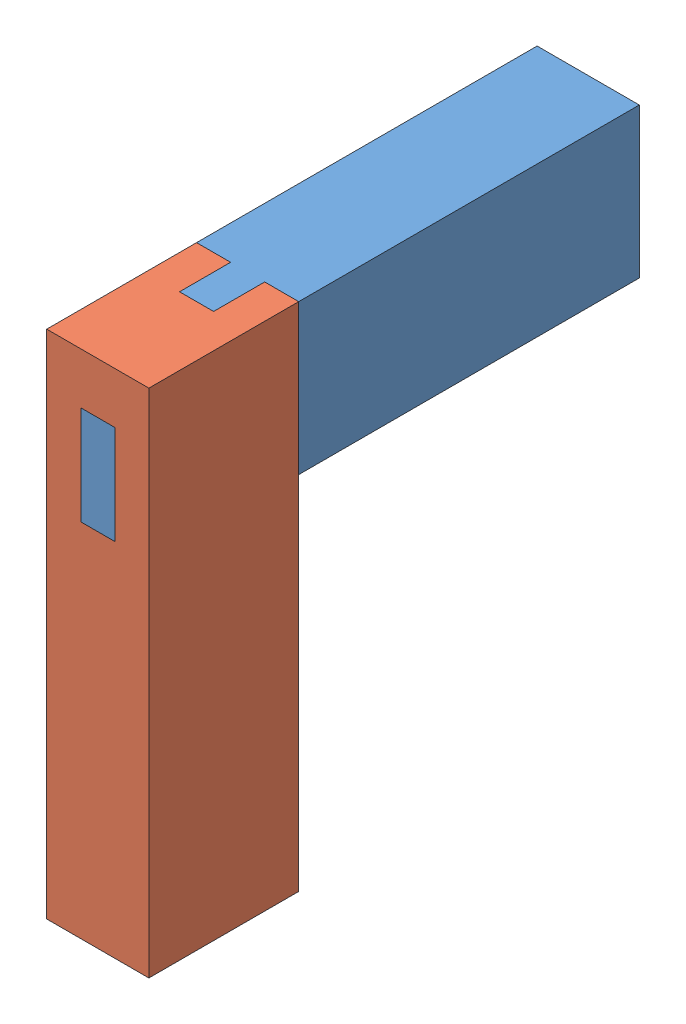
SolidWorks assembly M AND TENON EXPLODE, configuration Default. Lengths in mm.
Overall size (30 150 214.76).
2 component instances, 2 part files, 3 mates.
Components (placement in the parent):
- TENON-1: TENON [Default] at (-2.0324 11.2822 -9.248) size (30 44 144)
- MORTISE-1: MORTISE [Default] at (-2.0324 55.2822 34.752) x (1 0 0) z (0 1 0) size (30 44 150)
Mates (geometry in assembly coordinates):
- Coincident1: coincident anti-aligned: line of TENON-1 through (7.9676 11.2822 -9.248) axis (1 0 0); line of MORTISE-1 through (17.9676 11.2822 -9.248) axis (-1 0 0)
- Coincident2: coincident anti-aligned: line of TENON-1 through (17.9676 55.2822 5.752) axis (-1 0 0); line of MORTISE-1 through (7.9676 55.2822 5.752) axis (1 0 0)
- Coincident3: coincident anti-aligned: plane of TENON-1 through (7.9676 55.2822 5.752) normal (-1 0 0); plane of MORTISE-1 through (7.9676 55.2822 5.752) normal (1 0 0)
